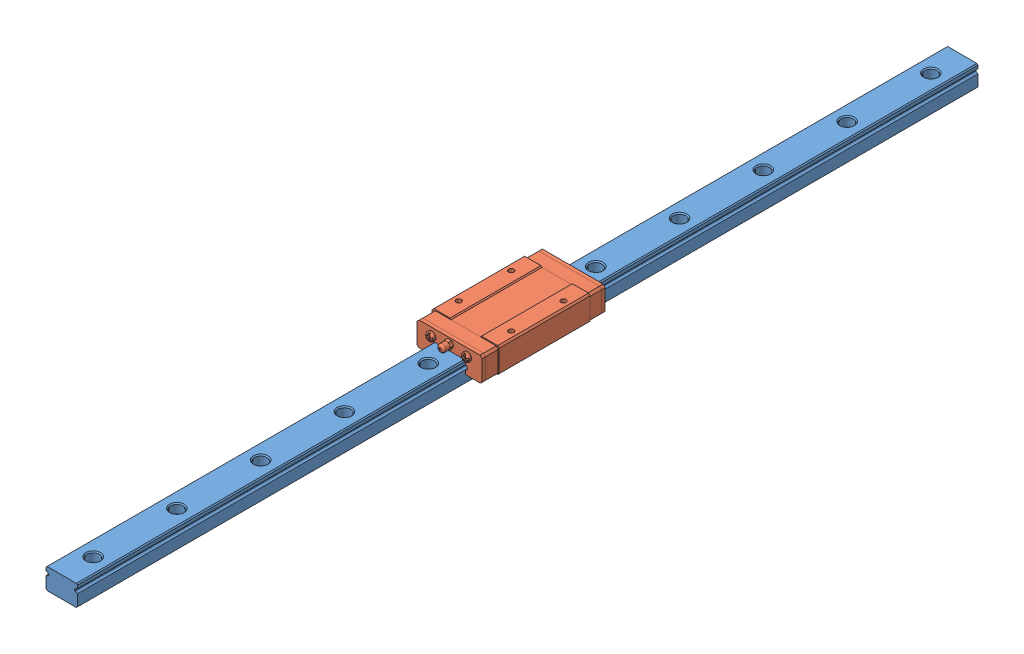
SolidWorks assembly MGN15H-430, configuration 預設. Lengths in mm.
Overall size (32 16 430).
2 component instances, 2 part files, 3 mates.
Components (placement in the parent):
- MGNR15-1: MGNR15 [Default] at origin size (15 10 430)
- MGN15H-1: MGN15H [Default] at (0 0 193.6902) size (32 12 64.87)
Mates (geometry in assembly coordinates):
- 同軸心1: concentric aligned: cylinder of MGN15H-1 through (7.5 7 239.2902) axis (0 0 -1) radius 1.0308; cylinder of MGNR15-1 through (7.5 7 430) axis (0 0 -1) radius 1.0308
- 同軸心2: concentric aligned: cylinder of MGN15H-1 through (-7.5 7 239.2902) axis (0 0 -1) radius 1.0308; cylinder of MGNR15-1 through (-7.5 7 430) axis (0 0 -1) radius 1.0308
- 重合/共線/共點3: coordinate: point of MGNR15-1; point of assembly
